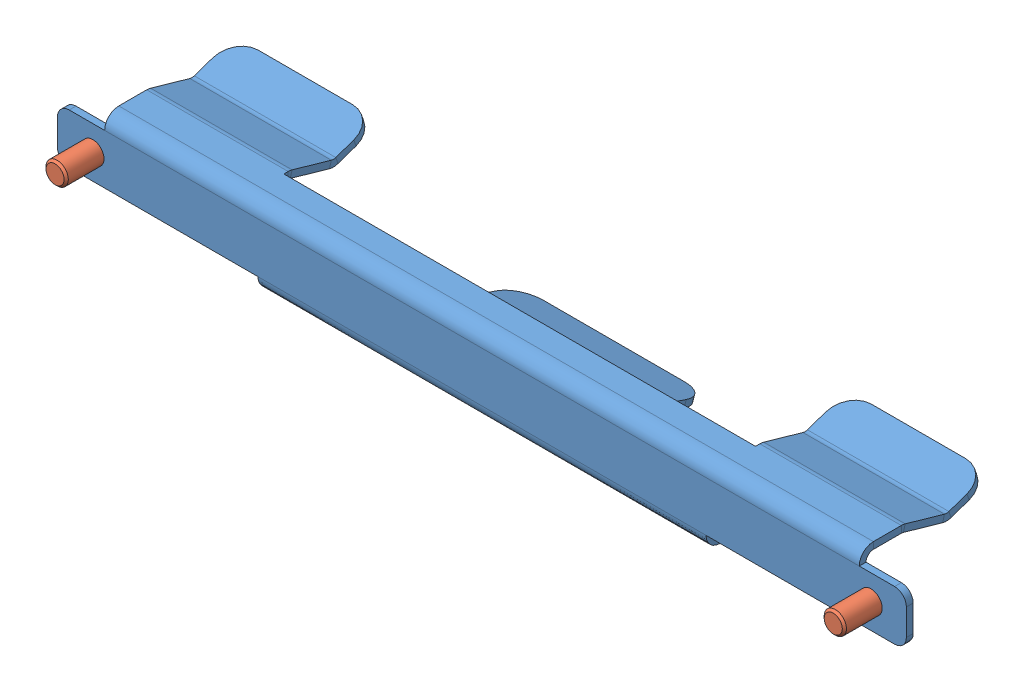
SolidWorks assembly 619012142, configuration Default. Lengths in mm.
Overall size (114.3 11.13 22.89).
5 component instances, 3 part files, 8 mates.
Components (placement in the parent):
- 619012142_01-1: 619012142_01 [Default] at origin size (114.3 11.13 17.8)
- PEM FH-M3-6 X-5: PEM FH-M3-6 X [PEM FH-M3-6 X] at (52.3875 0 -0.9119) x (0 0 1) z (-1 0 0) (suppressed, hidden)
- PEM FH-M3-6 X-4: PEM FH-M3-6 X [PEM FH-M3-6 X] at (-52.3875 0 -0.9119) x (0 0 1) z (-1 0 0) (suppressed, hidden)
- FH4-M3-6 X_REP-1: FH4-M3-6 X_REP [Default] at (52.3875 0 -0.9119) x (0 0 -1) z (1 0 0) size (6 4.5 4.5)
- FH4-M3-6 X_REP-2: FH4-M3-6 X_REP [Default] at (-52.3875 0 -0.9119) x (0 0 -1) z (1 0 0) size (6 4.5 4.5)
Mates (geometry in assembly coordinates):
- Concentric1: concentric: cylinder of 619012142_01-1 through (52.3875 0 0) axis (0 0 1) radius 1.5; cylinder of PEM FH-M3-6 X-5 through (52.3875 0 -0.9119) axis (0 0 -1) radius 2.0875
- Coincident1: coincident: plane of 619012142_01-1 through (57.15 -3.3655 -0.9119) normal (0 0 -1); plane of PEM FH-M3-6 X-5 through (52.3875 0 -0.9119) normal (0 0 -1)
- Concentric21: concentric: cylinder of 619012142_01-1 through (-52.3875 0 0) axis (0 0 1) radius 1.5; cylinder of PEM FH-M3-6 X-4 through (-52.3875 0 -0.9119) axis (0 0 -1) radius 2.0875
- Coincident21: coincident: plane of 619012142_01-1 through (57.15 -3.3655 -0.9119) normal (0 0 -1); plane of PEM FH-M3-6 X-4 through (-52.3875 0 -0.9119) normal (0 0 -1)
- Concentric22: concentric: cylinder of 619012142_01-1 through (52.3875 0 0) axis (0 0 1) radius 1.5; cylinder of FH4-M3-6 X_REP-1 through (52.3875 0 -100.2515) axis (0 0 -1) radius 1.5
- Coincident22: coincident: plane of 619012142_01-1 through (57.15 -3.3655 -0.9119) normal (0 0 -1); plane of FH4-M3-6 X_REP-1 through (52.3875 0 -0.9119) normal (0 0 -1)
- Concentric23: concentric: cylinder of 619012142_01-1 through (-52.3875 0 0) axis (0 0 1) radius 1.5; cylinder of FH4-M3-6 X_REP-2 through (-52.3875 0 -100.2515) axis (0 0 -1) radius 1.5
- Coincident23: coincident: plane of 619012142_01-1 through (57.15 -3.3655 -0.9119) normal (0 0 -1); plane of FH4-M3-6 X_REP-2 through (-52.3875 0 -0.9119) normal (0 0 -1)
